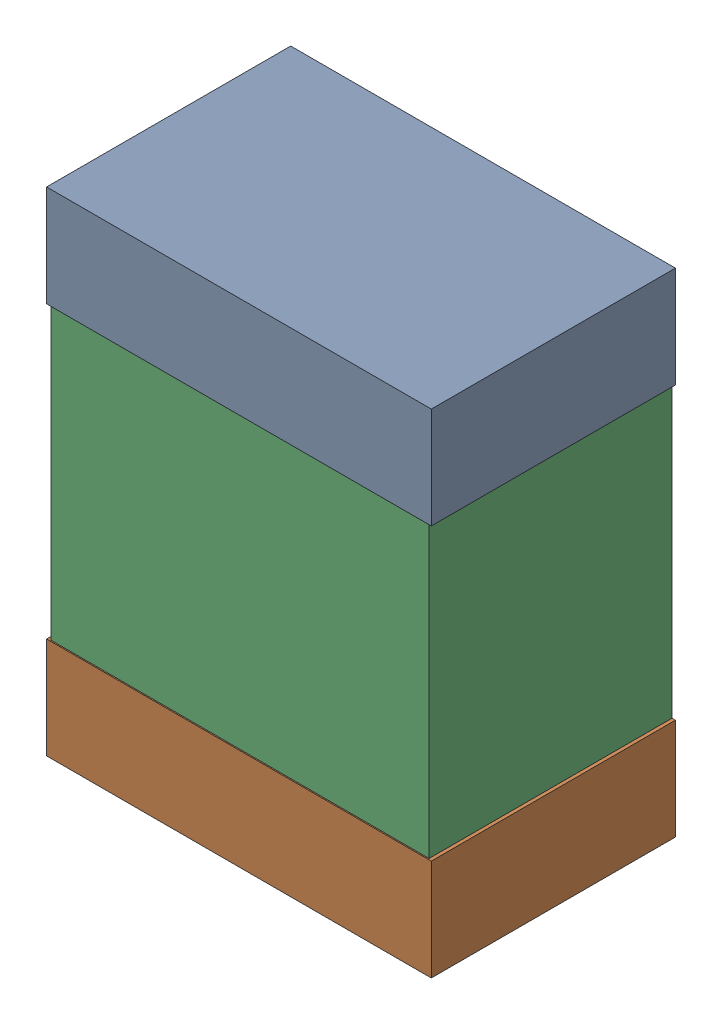
SolidWorks assembly CoutMByp1Kanaloa_v2.0.0_Power, configuration Default. Lengths in mm.
Overall size (2.85 3.65 1.81).
6 component instances, 2 part files, 0 mates.
Components (placement in the parent):
- 334789552-1: 334789552 [Default] at (53.65 51.375 0) size (2.85 0.75 1.81)
  - Extruded_9-1: Extruded_9 [Default] at origin size (2.85 0.75 1.81)
- 334789552-2: 334789552 [Default] at (53.65 48.475 0) size (2.85 0.75 1.81)
  - Extruded_9-1: Extruded_9 [Default] at origin size (2.85 0.75 1.81)
- 334789424-1: 334789424 [Default] at (53.65 49.925 0) size (2.8 3.6 1.8)
  - Extruded_10-1: Extruded_10 [Default] at origin size (2.8 3.6 1.8)
